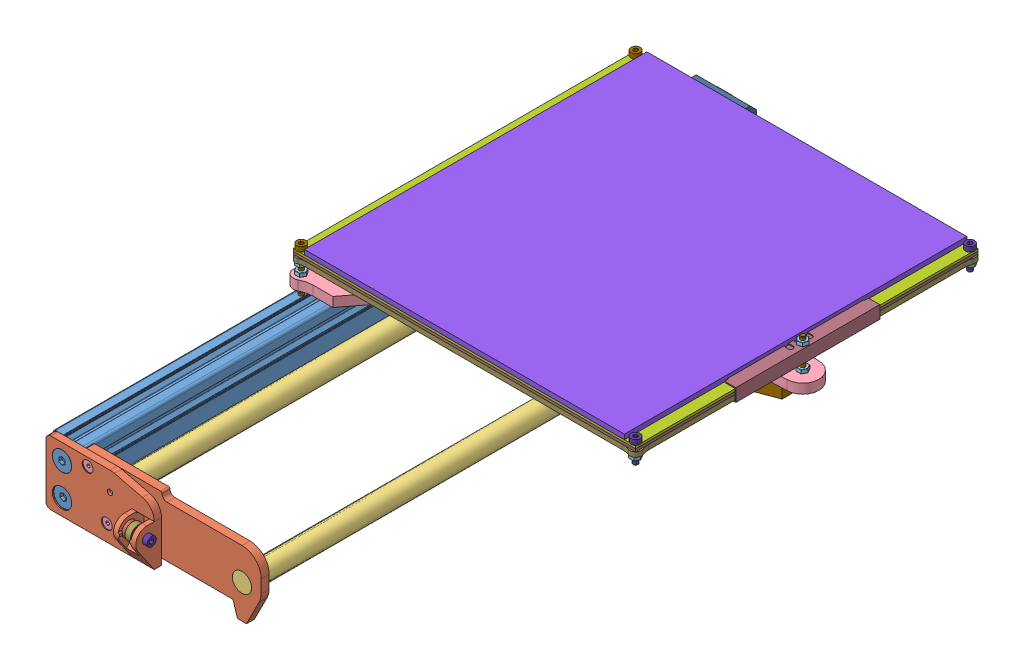
SolidWorks assembly 750Y, configuration Default. Lengths in mm.
Overall size (237.4 78 421.57).
82 component instances, 32 part files, 159 mates.
Components (placement in the parent):
- 458-1: 458 [Default] at origin size (20 40 350)
- 547-1: 547 [Default] at (0 10 350) size (67.7 40 32.1)
- 402-1: 402 [Default] at (30 18 0) x (0.324904 -0.945747 0) z (0 0 1) size (12 12 350)
- 681-1: 681 [Default] at (101.9 38 97.838) x (0 0 -1) z (0 1 0) size (219 224 6)
- 444-1: 444 [Default] at (30 18 36.838) x (0.795933 -0.605384 0) z (0 0 1) size (21 21 30)
- 444-2: 444 [Default] at (30 18 128.838) x (0.061759 0.998091 0) z (0 0 1) size (21 21 30)
- 549-4: 549 [Default] at (30 18 128.838) x (0 -1 0) z (0 0 1) size (36.4 41.5 26)
- 550-4: 550 [Default] at (30 18 66.838) x (0 1 0) z (0 0 -1) size (36.4 41.5 37)
- 529-1: 529 [Default] at (13.5 18 97.838) x (0 0 -1) z (1 0 0) size (172 46 6)
- 530-1: 530 [Default] at (30 18 94.838) size (183 47.02 6)
- 408-1: 408 [Default] at (-0.75 9 -25.7) x (0 0 1) z (1 0 0) size (50.7 42 57.75)
- 548-1: 548 [Default] at (0 10 0) x (1 0 0) z (0 0 -1) size (48 42 66.5)
- 279-1: 279 [Default] at (51.2 7.9393 358.0393) x (0 0.707107 0.707107) z (1 0 0) size (10 10 4)
- 1047-2: 1047 [Default] at (101.9 56.1 97.838) x (0 0 1) z (0 -1 0) size (214 214 1.6)
- 543-3: 543 [Default] at (41 5 58.838) x (0 -0.961946 -0.273238) z (1 0 0) size (5.7 5.7 33)
- 543-4: 543 [Default] at (41 5 136.838) x (0 -0.299784 -0.954007) z (1 0 0) size (5.7 5.7 33)
- 543-5: 543 [Default] at (41 31 58.838) x (0 0.49265 -0.870228) z (1 0 0) size (5.7 5.7 33)
- 429-1: 429 [Default] at (36.325 -6.5 -41.2) x (0 0 -1) z (1 0 0) size (6.75 6.75 8)
- 429-2: 429 [Default] at (36.325 24.5 -10.2) x (0 0 -1) z (1 0 0) size (6.75 6.75 8)
- 116-3: 116 [Default] at (14.95 0.1 11) x (0 0 -1) z (1 0 0) size (7.8 7.8 12)
- 116-4: 116 [Default] at (15 0 339) x (0 0 -1) z (1 0 0) size (7.8 7.8 12)
- 257-1: 257 [Default] at (57.7 9 359.1) x (0 0 -1) z (1 0 0) size (5.7 5.7 15)
- 543-6: 543 [Default] at (41 31 136.838) x (0 -0.999989 -0.004729) z (1 0 0) size (5.7 5.7 33)
- 212-1: 212 [Default] at (28 18 143.322) x (1 0 0) z (0 0 -1) size (7 7 0.5)
- 414-1: 414 [Default] at (0 20 351.5) size (12 12 16)
- 414-2: 414 [Default] at (0 0 350.7) size (12 12 16)
- 414-3: 414 [Default] at (0 20 -6.65) size (12 12 16)
- 414-4: 414 [Default] at (0 0 -6.65) size (12 12 16)
- 531-1: 531 [Default] at (30 18 0) size (115 45 5)
- 402-2: 402 [Default] at (108 6 0) x (-0.810971 0.585087 0) z (0 0 1) size (12 12 350)
- 531-2: 531 [Default] at (30 18 345) size (115 45 5)
- 444-3: 444 [Default] at (108 6 112.838) x (0.977925 0.208956 0) z (0 0 -1) size (21 21 30)
- 185-1: 185 [Default] at (38 14.1 -5.2) x (0 -1 0) z (1 0 0) size (20 11 6)
- 466-1: 466 [Default] at (16 25 -5.575) size (6.75 6.75 12)
- 466-2: 466 [Default] at (28 0 -5.575) size (6.75 6.75 12)
- 258-1: 258 [Default] at (16 25 342.6) size (6.35 5.5 2.4)
- 258-2: 258 [Default] at (28 0 345) x (-0.5 -0.866025 0) z (0 0 -1) size (6.35 5.5 2.4)
- 465-1: 465 [Default] at (-18 -6.5 -10.2) x (0 0.234808 0.972042) z (-1 0 0) size (5.7 5.7 53)
- 466-3: 466 [Default] at (28 0 352.275) size (6.75 6.75 12)
- 258-3: 258 [Default] at (28 0 5) size (6.35 5.5 2.4)
- 466-4: 466 [Default] at (16 25 352.275) size (6.75 6.75 12)
- 258-4: 258 [Default] at (16 25 5) x (-0.923728 -0.383049 0) z (0 0 -1) size (6.35 5.5 2.4)
- 498-1: 498 [Default] at (101.9 57.6 97.838) x (0 0 1) z (0 -1 0) size (214 214 1.5)
- 125-1: 125 [Default] at (101.9 57.6 97.838) x (0 0 1) z (0 1 0) size (214 200 3)
- 112-9: 112 [Default] at (-2.6 57.6 202.338) x (0.999023 0 -0.04419) z (0 1 0) size (5.7 5.7 28)
- 258-5: 258 [Default] at (-2.6 49.1 202.338) x (1 0 0) z (0 1 0) size (6.35 5.5 2.4)
- 112-10: 112 [Default] at (206.4 38 97.838) x (0.57539 0 0.817879) z (0 -1 0) size (5.7 5.7 28)
- 257-9: 257 [Default] at (206.4 57.6 -6.662) x (1 0 0) z (0 1 0) size (5.7 5.7 15)
- 112-11: 112 [Default] at (-2.6 57.6 -6.662) x (1 0 0) z (0 1 0) size (5.7 5.7 28)
- 257-10: 257 [Default] at (206.4 57.6 202.338) x (-0.938216 0 0.34605) z (0 1 0) size (5.7 5.7 15)
- 258-6: 258 [Default] at (206.4 49.1 -6.662) x (1 0 0) z (0 1 0) size (6.35 5.5 2.4)
- 258-7: 258 [Default] at (206.4 58.6967 97.838) x (0.969959 0 -0.24327) z (0 1 0) size (6.35 5.5 2.4)
- 258-8: 258 [Default] at (206.4 49.1 202.338) x (1 0 -0.000756) z (0 1 0) size (6.35 5.5 2.4)
- 258-9: 258 [Default] at (206.4 52.1 97.838) x (0.866025 0 0.5) z (0 1 0) size (6.35 5.5 2.4)
- 258-10: 258 [Default] at (-2.6 49.1 -6.662) x (1 0 0) z (0 1 0) size (6.35 5.5 2.4)
- 497-3: 497 [Default] at (4 0 342) x (0 -1 0) z (1 0 0) size (16 6 5.5)
- 258-13: 258 [Default] at (206.4 44 97.838) x (1 0 0) z (0 1 0) size (6.35 5.5 2.4)
- 258-14: 258 [Default] at (-2.6 44 202.338) x (1 0 0) z (0 1 0) size (6.35 5.5 2.4)
- 258-15: 258 [Default] at (-2.6 44 -6.662) x (1 0 0) z (0 1 0) size (6.35 5.5 2.4)
- 258-16: 258 [Default] at (47.5 30.1 97.838) x (0 0 -1) z (0 1 0) size (6.35 5.5 2.4)
- 212-2: 212 [Default] at (47.5 32.5 97.838) x (1 0 0) z (0 1 0) size (7 7 0.5)
- 544-5: 544 [Default] at (47.5 43.725 97.838) x (1 0 0) z (0 1 0) size (6.75 6.75 16)
- 544-7: 544 [Default] at (16.5 43.725 69.838) x (-0.20031 0 -0.979733) z (0 1 0) size (6.75 6.75 16)
- 544-8: 544 [Default] at (16.5 43.725 125.838) x (1 0 0) z (0 1 0) size (6.75 6.75 16)
- 258-17: 258 [Default] at (16.5 30.1 69.838) x (0.5 0 0.866025) z (0 1 0) size (6.35 5.5 2.4)
- 258-18: 258 [Default] at (16.5 30.1 125.838) x (0.5 0 0.866025) z (0 1 0) size (6.35 5.5 2.4)
- 212-3: 212 [Default] at (16.5 32.5 125.838) x (0.9987 0 -0.050978) z (0 1 0) size (7 7 0.5)
- 212-4: 212 [Default] at (16.5 32.5 69.838) x (0.896423 0 -0.443199) z (0 1 0) size (7 7 0.5)
- 497-4: 497 [Default] at (4 0.1 14) x (0 -1 0) z (1 0 0) size (16 6 5.5)
- 258-19: 258 [Default] at (11.1 5 136.838) x (0 -0.988673 0.150084) z (1 0 0) size (6.35 5.5 2.4)
- 258-21: 258 [Default] at (11.1 31 58.838) x (0 -0.988673 0.150084) z (1 0 0) size (6.35 5.5 2.4)
- 258-22: 258 [Default] at (11.1 5 58.838) x (0 -0.988673 0.150084) z (1 0 0) size (6.35 5.5 2.4)
- 258-23: 258 [Default] at (11.1 31 136.838) x (0 -0.988673 0.150084) z (1 0 0) size (6.35 5.5 2.4)
- 544-9: 544 [Default] at (147.5 43.725 97.838) x (1 0 0) z (0 1 0) size (6.75 6.75 16)
- 258-24: 258 [Default] at (147.5 30.1 97.838) x (0 0 -1) z (0 1 0) size (6.35 5.5 2.4)
- 212-5: 212 [Default] at (147.5 32.5 97.838) x (1 0 0) z (0 1 0) size (7 7 0.5)
- 258-25: 258 [Default] at (-2.6 35.6 202.338) x (1 0 0) z (0 1 0) size (6.35 5.5 2.4)
- 258-26: 258 [Default] at (-2.6 35.6 -6.662) x (1 0 0) z (0 1 0) size (6.35 5.5 2.4)
- 1044-1: 1044 [Default] at (101.9 51.5 97.838) x (0 0 -1) z (0 1 0) size (216.07 216.07 3)
- 575-1: 575 [Default] at (209.5 54.5281 97.838) x (0 0 1) z (-1 0 0) size (90 8 28.3)
- 461-1: 461 [Default] at (-8.542 38.3733 30.9668) size (4.5 4.5 12.5)
- 461-2: 461 [Default] at (-8.5585 42.2431 13.8478) size (4.5 4.5 12.5)
Mates (geometry in assembly coordinates):
- Coincident60: coincident anti-aligned: plane of 547-1 through (-7 -7 350) normal (0 0 -1); plane of 458-1 through (9.8 -3.75 350) normal (0 0 1)
- Coincident121: coincident anti-aligned: plane of 458-1 through (9.8 -3.75 0) normal (0 0 -1); plane of 548-1 through (0 10 0) normal (0 0 1)
- Parallel12: parallel aligned: plane of 458-1 through (10 16.3 350) normal (1 0 0); plane of 548-1 through (38 -12 -4.5) normal (1 0 0)
- Concentric67: concentric aligned: cylinder of 458-1 through (0 20 350) axis (0 0 -1) radius 2.75; cylinder of 547-1 through (0 20 354.5) axis (0 0 -1) radius 3.1
- Concentric235: concentric aligned: cylinder of 458-1 through (0 0 350) axis (0 0 -1) radius 2.75; cylinder of 547-1 through (0 0 354.5) axis (0 0 -1) radius 3.1
- Concentric243: concentric anti-aligned: cylinder of 458-1 through (0 20 350) axis (0 0 -1) radius 2.75; cylinder of 548-1 through (0 20 -4.5) axis (0 0 1) radius 3.15
- Concentric68: concentric anti-aligned: cylinder of 547-1 through (-10 9 359.1) axis (1 0 0) radius 1.65; cylinder of 279-1 through (53.7 9 359.1) axis (-1 0 0) radius 1.5
- Coincident127: coincident anti-aligned: plane of 547-1 through (48.7 9 359.1) normal (1 0 0); plane of 279-1 through (48.7 10.0607 360.1607) normal (-1 0 0)
- Concentric164: concentric aligned: cylinder of 116-4 through (5.3 0 339) axis (1 0 0) radius 2; cylinder of 547-1 through (-10 0 339) axis (1 0 0) radius 2.1
- Coincident217: coincident: cone of 547-1 through (15.5 0 339) axis (-1 0 0); circle of 116-4
- Concentric165: concentric aligned: cylinder of 547-1 through (-10 9 359.1) axis (1 0 0) radius 1.65; cylinder of 257-1 through (45.7 9 359.1) axis (1 0 0) radius 1.5
- Coincident218: coincident anti-aligned: plane of 547-1 through (57.7 30 354.5) normal (1 0 0); plane of 257-1 through (57.7 9 359.1) normal (-1 0 0)
- Coincident277: coincident: cone of 547-1 through (0 0 353.8) axis (0 0 -1); circle of 414-2
- Coincident278: coincident aligned: plane of 547-1 through (-7 -7 354.5) normal (0 0 1); circle of 414-1
- Concentric234: concentric anti-aligned: cylinder of 547-1 through (0 0 354.5) axis (0 0 -1) radius 3.1; cylinder of 414-2 through (0 0 337.7) axis (0 0 1) radius 3
- Concentric240: concentric anti-aligned: cylinder of 547-1 through (0 20 354.5) axis (0 0 -1) radius 3.1; cylinder of 414-1 through (0 20 338.5) axis (0 0 1) radius 3
- Concentric251: concentric anti-aligned: cylinder of 547-1 through (16 25 366.1) axis (0 0 -1) radius 1.65; cylinder of 466-4 through (16 25 341.925) axis (0 0 1) radius 1.5
- Coincident302: coincident: cone of 547-1 through (16 25 352.2) axis (0 0 -1); circle of 466-4
- Concentric252: concentric anti-aligned: cylinder of 547-1 through (28 0 366.1) axis (0 0 -1) radius 1.65; cylinder of 466-3 through (28 0 341.925) axis (0 0 1) radius 1.5
- Coincident303: coincident: cone of 547-1 through (28 0 352.2) axis (0 0 -1); circle of 466-3
- Concentric56: concentric anti-aligned: cylinder of 402-1 through (30 18 350) axis (0 0 -1) radius 6; cylinder of 444-1 through (30 18 36.838) axis (0 0 1) radius 6
- Concentric95: concentric anti-aligned: cylinder of 402-1 through (30 18 350) axis (0 0 -1) radius 6; cylinder of 444-2 through (30 18 128.838) axis (0 0 1) radius 6
- Concentric231: concentric aligned: cylinder of 402-1 through (30 18 350) axis (0 0 -1) radius 6; cylinder of 531-2 through (30 18 350) axis (0 0 -1) radius 5.98
- Concentric85: concentric anti-aligned: cylinder of 1047-2 through (-2.6 54.5 -6.662) axis (0 1 0) radius 1.5; cylinder of 681-1 through (-2.6 44 -6.662) axis (0 -1 0) radius 1.5
- Coincident300: coincident anti-aligned: plane of 681-1 through (-20.1 38 3.0204) normal (0 -1 0); plane of 529-1 through (19.5 38 105.338) normal (0 1 0)
- Width10: width anti-aligned: plane of 681-1 through (194.5 44 100.888) normal (-1 0 0); plane of 681-1 through (178.5 44 100.888) normal (1 0 0); plane of 530-1 through (194.5 44 100.838) normal (1 0 0); plane of 530-1 through (178.5 38 100.838) normal (-1 0 0)
- Width11: width anti-aligned: plane of 681-1 through (19.6 44 90.338) normal (0 0 1); plane of 681-1 through (19.6 44 105.338) normal (0 0 -1); plane of 529-1 through (19.5 38 90.338) normal (0 0 -1); plane of 529-1 through (19.5 38 105.338) normal (0 0 1)
- Concentric148: concentric aligned: cylinder of 444-1 through (30 18 36.838) axis (0 0 1) radius 10.5; cylinder of 550-4 through (30 18 40.838) axis (0 0 1) radius 10.5
- Coincident299: coincident aligned: plane of 550-4 through (30 18 66.838) normal (0 0 1); plane of 444-1 through (34.7756 14.3677 66.838) normal (0 0 1)
- Concentric97: concentric anti-aligned: cylinder of 444-2 through (30 18 128.838) axis (0 0 1) radius 10.5; cylinder of 549-4 through (30 18 154.838) axis (0 0 -1) radius 10.5
- Coincident298: coincident aligned: plane of 549-4 through (30 18 128.838) normal (0 0 -1); plane of 444-2 through (30.6485 28.48 128.838) normal (0 0 -1)
- Width13: width anti-aligned: plane of 529-1 through (19.5 44 100.838) normal (0 0 -1); plane of 529-1 through (19.5 44 94.838) normal (0 0 1); plane of 530-1 through (30 18 100.838) normal (0 0 1); plane of 530-1 through (30 18 94.838) normal (0 0 -1)
- Concentric106: concentric aligned: cylinder of 529-1 through (13.5 5 58.838) axis (1 0 0) radius 2; cylinder of 543-3 through (11 5 58.838) axis (1 0 0) radius 1.5
- Concentric107: concentric aligned: cylinder of 529-1 through (13.5 5 136.838) axis (1 0 0) radius 2; cylinder of 543-4 through (11 5 136.838) axis (1 0 0) radius 1.5
- Concentric147: concentric aligned: cylinder of 529-1 through (13.5 31 58.838) axis (1 0 0) radius 2; cylinder of 543-5 through (11 31 58.838) axis (1 0 0) radius 1.5
- Concentric166: concentric aligned: cylinder of 529-1 through (13.5 31 136.838) axis (1 0 0) radius 2; cylinder of 543-6 through (11 31 136.838) axis (1 0 0) radius 1.5
- Width9: width aligned: plane of 444-3 through (118.2682 8.194 112.838) normal (0 0 1); plane of 444-3 through (113.8676 7.2537 82.838) normal (0 0 -1); plane of 530-1 through (30 18 100.838) normal (0 0 1); plane of 530-1 through (30 18 94.838) normal (0 0 -1)
- Concentric250: concentric aligned: cylinder of 530-1 through (108 6 100.838) axis (0 0 -1) radius 10.45; cylinder of 444-3 through (108 6 112.838) axis (0 0 -1) radius 10.5
- Coincident123: coincident anti-aligned: plane of 408-1 through (33 9 -25.7) normal (1 0 0); plane of 548-1 through (33 30 -50.5) normal (-1 0 0)
- Parallel26: parallel aligned: plane of 408-1 through (33 -8.007 -4.7) normal (0 0 1); plane of 548-1 through (0 10 0) normal (0 0 1)
- Concentric143: concentric aligned: cylinder of 408-1 through (35 9 -25.7) axis (-1 0 0) radius 11; cylinder of 548-1 through (38.0001 9 -25.7) axis (-1 0 0) radius 11.1
- Concentric163: concentric anti-aligned: cone of 548-1 through (17.5 0.1 11) axis (-1 0 0); cylinder of 116-3 through (5.25 0.1 11) axis (1 0 0) radius 2
- Coincident216: coincident: cone of 548-1 through (17.5 0.1 11) axis (-1 0 0); circle of 116-3
- Concentric209: concentric aligned: cylinder of 548-1 through (0 0 -4.5) axis (0 0 1) radius 3.15; cylinder of 414-4 through (0 0 -19.65) axis (0 0 1) radius 3
- Coincident273: coincident: cone of 548-1 through (0 0 -3.8) axis (0 0 1); circle of 414-4
- Concentric210: concentric aligned: cylinder of 548-1 through (0 20 -4.5) axis (0 0 1) radius 3.15; cylinder of 414-3 through (0 20 -19.65) axis (0 0 1) radius 3
- Coincident274: coincident: cone of 548-1 through (0 20 -3.8) axis (0 0 1); circle of 414-3
- Coincident291: coincident anti-aligned: plane of 548-1 through (0 10 0) normal (0 0 1); plane of 531-1 through (10 23.8 0) normal (0 0 -1)
- Parallel36: parallel anti-aligned: plane of 548-1 through (10 -6 16) normal (0 1 0); plane of 531-1 through (10.8 -6 5) normal (0 -1 0)
- Concentric244: concentric aligned: cylinder of 548-1 through (16 25 -50.501) axis (0 0 1) radius 1.65; cylinder of 466-1 through (16 25 -15.925) axis (0 0 1) radius 1.5
- Coincident293: coincident: cone of 548-1 through (16 25 -2.2) axis (0 0 1); circle of 466-1
- Concentric245: concentric aligned: cylinder of 548-1 through (28 0 -50.501) axis (0 0 1) radius 1.65; cylinder of 466-2 through (28 0 -15.925) axis (0 0 1) radius 1.5
- Coincident294: coincident: cone of 548-1 through (28 0 -2.2) axis (0 0 1); circle of 466-2
- Coincident304: coincident aligned: plane of 531-1 through (10 23.8 5) normal (0 0 1); plane of 258-4 through (16 25 5) normal (0 0 1)
- Coincident305: coincident anti-aligned: plane of 531-1 through (10 23.8 5) normal (0 0 1); plane of 258-3 through (28 0 5) normal (0 0 -1)
- Concentric232: concentric aligned: cylinder of 402-2 through (108 6 350) axis (0 0 -1) radius 6; cylinder of 531-2 through (108 6 350) axis (0 0 -1) radius 5.98
- Concentric233: concentric aligned: cylinder of 402-2 through (108 6 350) axis (0 0 -1) radius 6; cylinder of 444-3 through (108 6 112.838) axis (0 0 -1) radius 6
- Coincident295: coincident anti-aligned: plane of 531-2 through (10 23.8 345) normal (0 0 -1); plane of 258-1 through (16 25 345) normal (0 0 1)
- Coincident297: coincident anti-aligned: plane of 531-2 through (10 23.8 345) normal (0 0 -1); plane of 258-2 through (28 0 345) normal (0 0 1)
- Concentric246: concentric anti-aligned: cylinder of 466-1 through (16 25 -15.925) axis (0 0 1) radius 1.5; cylinder of 258-1 through (16 25 345) axis (0 0 -1) radius 1.25
- Concentric247: concentric aligned: cylinder of 466-2 through (28 0 -15.925) axis (0 0 1) radius 1.5; cylinder of 258-2 through (28 0 342.6) axis (0 0 1) radius 1.25
- Concentric254: concentric anti-aligned: cylinder of 466-3 through (28 0 341.925) axis (0 0 1) radius 1.5; cylinder of 258-3 through (28 0 7.4) axis (0 0 -1) radius 1.25
- Concentric253: concentric aligned: cylinder of 466-4 through (16 25 341.925) axis (0 0 1) radius 1.5; cylinder of 258-4 through (16 25 2.6) axis (0 0 1) radius 1.25
- Concentric255: concentric anti-aligned: cylinder of 681-1 through (206.4 44 97.838) axis (0 -1 0) radius 1.5; cylinder of 1047-2 through (206.4 54.5 97.838) axis (0 1 0) radius 1.5
- Coincident306: coincident anti-aligned: plane of 1047-2 through (101.9 56.1 97.838) normal (0 1 0); plane of 498-1 through (101.9 56.1 97.838) normal (0 -1 0)
- Coincident307: coincident aligned: plane of 1047-2 through (208.9 54.5 -9.162) normal (1 0 0); plane of 498-1 through (208.9 56.1 -9.162) normal (1 0 0)
- Coincident308: coincident aligned: plane of 1047-2 through (208.9 54.5 -9.162) normal (0 0 -1); plane of 498-1 through (208.9 56.1 -9.162) normal (0 0 -1)
- Coincident346: coincident anti-aligned: plane of 498-1 through (101.9 57.6 97.838) normal (0 1 0); plane of 125-1 through (101.9 57.6 97.838) normal (0 -1 0)
- Coincident348: coincident aligned: plane of 498-1 through (208.9 56.1 -9.162) normal (0 0 -1); plane of 125-1 through (201.9 60.6 -9.162) normal (0 0 -1)
- Width12: width aligned: plane of 498-1 through (-5.1 56.1 -9.162) normal (-1 0 0); plane of 498-1 through (208.9 56.1 -9.162) normal (1 0 0); plane of 125-1 through (1.9 60.6 -9.162) normal (-1 0 0); plane of 125-1 through (201.9 60.6 -9.162) normal (1 0 0)
- Concentric256: concentric anti-aligned: cylinder of 257-10 through (206.4 45.6 202.338) axis (0 1 0) radius 1.5; cylinder of 258-8 through (206.4 51.5 202.338) axis (0 -1 0) radius 1.25
- Concentric257: concentric anti-aligned: cylinder of 112-9 through (-2.6 32.6 202.338) axis (0 1 0) radius 1.5; cylinder of 258-5 through (-2.6 51.5 202.338) axis (0 -1 0) radius 1.25
- Concentric258: concentric anti-aligned: cylinder of 112-11 through (-2.6 32.6 -6.662) axis (0 1 0) radius 1.5; cylinder of 258-10 through (-2.6 51.5 -6.662) axis (0 -1 0) radius 1.25
- Concentric259: concentric aligned: cylinder of 498-1 through (206.4 56.1 202.338) axis (0 1 0) radius 1.6; cylinder of 257-10 through (206.4 45.6 202.338) axis (0 1 0) radius 1.5
- Coincident350: coincident anti-aligned: plane of 498-1 through (101.9 57.6 97.838) normal (0 1 0); plane of 257-10 through (206.4 57.6 202.338) normal (0 -1 0)
- Coincident352: coincident anti-aligned: plane of 498-1 through (101.9 57.6 97.838) normal (0 1 0); plane of 112-9 through (-2.6 57.6 202.338) normal (0 -1 0)
- Concentric260: concentric aligned: cylinder of 498-1 through (-2.6 56.1 202.338) axis (0 1 0) radius 1.6; cylinder of 112-9 through (-2.6 32.6 202.338) axis (0 1 0) radius 1.5
- Coincident354: coincident anti-aligned: plane of 498-1 through (101.9 57.6 97.838) normal (0 1 0); plane of 112-11 through (-2.6 57.6 -6.662) normal (0 -1 0)
- Concentric261: concentric aligned: cylinder of 498-1 through (-2.6 56.1 -6.662) axis (0 1 0) radius 1.6; cylinder of 112-11 through (-2.6 32.6 -6.662) axis (0 1 0) radius 1.5
- Concentric262: concentric anti-aligned: cylinder of 1047-2 through (206.4 54.5 97.838) axis (0 1 0) radius 1.5; cylinder of 112-10 through (206.4 63 97.838) axis (0 -1 0) radius 1.5
- Concentric263: concentric aligned: cylinder of 498-1 through (206.4 56.1 -6.662) axis (0 1 0) radius 1.6; cylinder of 257-9 through (206.4 45.6 -6.662) axis (0 1 0) radius 1.5
- Coincident356: coincident anti-aligned: plane of 1047-2 through (101.9 54.5 97.838) normal (0 -1 0); plane of 258-9 through (206.4 54.5 97.838) normal (0 1 0)
- Concentric264: concentric aligned: cylinder of 112-10 through (206.4 63 97.838) axis (0 -1 0) radius 1.5; cylinder of 258-9 through (206.4 54.5 97.838) axis (0 -1 0) radius 1.25
- Concentric265: concentric anti-aligned: cylinder of 257-9 through (206.4 45.6 -6.662) axis (0 1 0) radius 1.5; cylinder of 258-6 through (206.4 51.5 -6.662) axis (0 -1 0) radius 1.25
- Coincident358: coincident anti-aligned: plane of 498-1 through (101.9 57.6 97.838) normal (0 1 0); plane of 257-9 through (206.4 57.6 -6.662) normal (0 -1 0)
- Concentric266: concentric aligned: cylinder of 112-10 through (206.4 63 97.838) axis (0 -1 0) radius 1.5; cylinder of 258-7 through (206.4 61.0967 97.838) axis (0 -1 0) radius 1.25
- Concentric267: concentric aligned: cylinder of 116-4 through (5.3 0 339) axis (1 0 0) radius 2; cylinder of 497-3 through (4 0 339) axis (1 0 0) radius 1.65
- Parallel37: parallel aligned: plane of 547-1 through (-7 -7 354.5) normal (0 0 1); plane of 497-3 through (4 0 342) normal (0 0 1)
- Coincident361: coincident anti-aligned: plane of 458-1 through (8.5 3.45 350) normal (-1 0 0); plane of 497-3 through (8.5 8 336) normal (1 0 0)
- Concentric270: concentric anti-aligned: cylinder of 112-11 through (-2.6 32.6 -6.662) axis (0 1 0) radius 1.5; cylinder of 258-15 through (-2.6 46.4 -6.662) axis (0 -1 0) radius 1.25
- Concentric271: concentric anti-aligned: cylinder of 112-9 through (-2.6 32.6 202.338) axis (0 1 0) radius 1.5; cylinder of 258-14 through (-2.6 46.4 202.338) axis (0 -1 0) radius 1.25
- Concentric272: concentric aligned: cylinder of 112-10 through (206.4 63 97.838) axis (0 -1 0) radius 1.5; cylinder of 258-13 through (206.4 46.4 97.838) axis (0 -1 0) radius 1.25
- Coincident368: coincident anti-aligned: plane of 681-1 through (-20.1 44 3.0204) normal (0 1 0); plane of 258-13 through (206.4 44 97.838) normal (0 -1 0)
- Concentric273: concentric anti-aligned: cylinder of 681-1 through (47.5 44 97.838) axis (0 -1 0) radius 2; cylinder of 544-5 through (47.5 29.375 97.838) axis (0 1 0) radius 1.5
- Concentric274: concentric anti-aligned: cylinder of 258-16 through (47.5 32.5 97.838) axis (0 -1 0) radius 1.25; cylinder of 544-5 through (47.5 29.375 97.838) axis (0 1 0) radius 1.5
- Concentric275: concentric anti-aligned: cylinder of 212-2 through (47.5 33 97.838) axis (0 -1 0) radius 1.6; cylinder of 544-5 through (47.5 29.375 97.838) axis (0 1 0) radius 1.5
- Concentric276: concentric anti-aligned: cylinder of 681-1 through (16.5 44 125.838) axis (0 -1 0) radius 2; cylinder of 544-8 through (16.5 29.375 125.838) axis (0 1 0) radius 1.5
- Concentric277: concentric anti-aligned: cylinder of 544-8 through (16.5 29.375 125.838) axis (0 1 0) radius 1.5; cylinder of 258-18 through (16.5 32.5 125.838) axis (0 -1 0) radius 1.25
- Concentric278: concentric anti-aligned: cylinder of 544-8 through (16.5 29.375 125.838) axis (0 1 0) radius 1.5; cylinder of 212-3 through (16.5 33 125.838) axis (0 -1 0) radius 1.6
- Concentric279: concentric anti-aligned: cylinder of 681-1 through (16.5 44 69.838) axis (0 -1 0) radius 2; cylinder of 544-7 through (16.5 29.375 69.838) axis (0 1 0) radius 1.5
- Concentric280: concentric anti-aligned: cylinder of 544-7 through (16.5 29.375 69.838) axis (0 1 0) radius 1.5; cylinder of 258-17 through (16.5 32.5 69.838) axis (0 -1 0) radius 1.25
- Concentric281: concentric anti-aligned: cylinder of 544-7 through (16.5 29.375 69.838) axis (0 1 0) radius 1.5; cylinder of 212-4 through (16.5 33 69.838) axis (0 -1 0) radius 1.6
- Coincident371: coincident anti-aligned: plane of 530-1 through (46.02 33 100.838) normal (0 -1 0); plane of 212-2 through (47.5 33 97.838) normal (0 1 0)
- Coincident372: coincident anti-aligned: plane of 258-16 through (47.5 32.5 97.838) normal (0 1 0); plane of 212-2 through (47.5 32.5 97.838) normal (0 -1 0)
- Parallel38: parallel anti-aligned: plane of 530-1 through (44.8 32.5 100.838) normal (1 0 0); plane of 258-16 through (44.75 32.5 96.2502) normal (-1 0 0)
- Coincident373: coincident: circle of 681-1; cone of 544-5 through (47.5 45.375 97.838) axis (0 -1 0)
- Coincident374: coincident anti-aligned: plane of 258-17 through (16.5 32.5 69.838) normal (0 1 0); plane of 212-4 through (16.5 32.5 69.838) normal (0 -1 0)
- Coincident375: coincident anti-aligned: plane of 529-1 through (13.5 33 71.318) normal (0 -1 0); plane of 212-4 through (16.5 33 69.838) normal (0 1 0)
- Parallel39: parallel anti-aligned: plane of 529-1 through (13.5 32.5 72.538) normal (0 0 -1); plane of 258-17 through (14.9123 32.5 72.588) normal (0 0 1)
- Coincident376: coincident: circle of 681-1; cone of 544-7 through (16.5 45.375 69.838) axis (0 -1 0)
- Coincident377: coincident anti-aligned: plane of 258-18 through (16.5 32.5 125.838) normal (0 1 0); plane of 212-3 through (16.5 32.5 125.838) normal (0 -1 0)
- Coincident378: coincident anti-aligned: plane of 529-1 through (13.5 33 127.318) normal (0 -1 0); plane of 212-3 through (16.5 33 125.838) normal (0 1 0)
- Parallel40: parallel anti-aligned: plane of 529-1 through (13.5 32.5 128.538) normal (0 0 -1); plane of 258-18 through (14.9123 32.5 128.588) normal (0 0 1)
- Coincident379: coincident: circle of 681-1; cone of 544-8 through (16.5 45.375 125.838) axis (0 -1 0)
- Concentric282: concentric aligned: cylinder of 116-3 through (5.25 0.1 11) axis (1 0 0) radius 2; cylinder of 497-4 through (4 0.1 11) axis (1 0 0) radius 1.65
- Coincident380: coincident anti-aligned: plane of 458-1 through (8.5 -3.55 350) normal (-1 0 0); plane of 497-4 through (8.5 -7.9 8) normal (1 0 0)
- Coincident385: coincident aligned: plane of 529-1 through (19.5 25 33.838) normal (1 0 0); plane of 530-1 through (19.5 44 100.838) normal (1 0 0)
- Coincident388: coincident anti-aligned: plane of 549-4 through (19.5 33 154.838) normal (-1 0 0); plane of 529-1 through (19.5 25 33.838) normal (1 0 0)
- Concentric285: concentric anti-aligned: cylinder of 549-4 through (55 31 136.838) axis (-1 0 0) radius 1.65; cylinder of 529-1 through (13.5 31 136.838) axis (1 0 0) radius 2
- Coincident389: coincident anti-aligned: plane of 550-4 through (19.5 26 40.838) normal (-1 0 0); plane of 529-1 through (19.5 25 33.838) normal (1 0 0)
- Concentric286: concentric anti-aligned: cylinder of 550-4 through (45 5 58.838) axis (-1 0 0) radius 1.65; cylinder of 529-1 through (13.5 5 58.838) axis (1 0 0) radius 2
- Coincident390: coincident anti-aligned: plane of 547-1 through (-7 -7 350) normal (0 0 -1); plane of 531-2 through (10 23.8 350) normal (0 0 1)
- Coincident392: coincident aligned: plane of 402-1 through (30 18 350) normal (0 0 1); plane of 531-2 through (10 23.8 350) normal (0 0 1)
- Concentric288: concentric aligned: cylinder of 547-1 through (16 25 366.1) axis (0 0 -1) radius 1.65; cylinder of 531-2 through (16 25 350) axis (0 0 -1) radius 1.65
- Coincident393: coincident anti-aligned: plane of 547-1 through (57.7 -6 354.5) normal (0 1 0); plane of 531-2 through (10.8 -6 350) normal (0 -1 0)
- Coincident394: coincident aligned: plane of 402-2 through (108 6 350) normal (0 0 1); plane of 531-2 through (10 23.8 350) normal (0 0 1)
- Coincident395: coincident anti-aligned: plane of 549-4 through (41 5 136.838) normal (1 0 0); plane of 543-4 through (41 5 136.838) normal (-1 0 0)
- Concentric289: concentric anti-aligned: cylinder of 543-4 through (11 5 136.838) axis (1 0 0) radius 1.5; cylinder of 258-19 through (13.5 5 136.838) axis (-1 0 0) radius 1.25
- Concentric290: concentric aligned: cylinder of 402-1 through (30 18 350) axis (0 0 -1) radius 6; cylinder of 531-1 through (30 18 5) axis (0 0 -1) radius 5.98
- Concentric291: concentric aligned: cylinder of 408-1 through (28 24.5 -10.2) axis (1 0 0) radius 1.5; cylinder of 429-2 through (29.975 24.5 -10.2) axis (1 0 0) radius 1.5
- Concentric292: concentric aligned: cylinder of 408-1 through (28 -6.5 -41.2) axis (1 0 0) radius 1.5; cylinder of 429-1 through (29.975 -6.5 -41.2) axis (1 0 0) radius 1.5
- Concentric293: concentric aligned: cylinder of 408-1 through (4.25 -6.5 -10.2) axis (-1 0 0) radius 1.5; cylinder of 465-1 through (32 -6.5 -10.2) axis (-1 0 0) radius 1.5
- Coincident396: coincident anti-aligned: plane of 529-1 through (13.5 25 33.838) normal (-1 0 0); plane of 258-19 through (13.5 5 136.838) normal (1 0 0)
- Coincident397: coincident anti-aligned: plane of 550-4 through (41 5 58.838) normal (1 0 0); plane of 543-3 through (41 5 58.838) normal (-1 0 0)
- Coincident399: coincident anti-aligned: plane of 550-4 through (41 31 58.838) normal (1 0 0); plane of 543-5 through (41 31 58.838) normal (-1 0 0)
- Coincident400: coincident anti-aligned: plane of 549-4 through (41 31 136.838) normal (1 0 0); plane of 543-6 through (41 31 136.838) normal (-1 0 0)
- Concentric294: concentric aligned: cylinder of 543-5 through (44 31 58.838) axis (-1 0 0) radius 2.85; cylinder of 258-21 through (13.5 31 58.838) axis (-1 0 0) radius 1.25
- Concentric295: concentric aligned: cylinder of 543-3 through (44 5 58.838) axis (-1 0 0) radius 2.85; cylinder of 258-22 through (13.5 5 58.838) axis (-1 0 0) radius 1.25
- Concentric296: concentric aligned: cylinder of 543-6 through (44 31 136.838) axis (-1 0 0) radius 2.85; cylinder of 258-23 through (13.5 31 136.838) axis (-1 0 0) radius 1.25
- Coincident401: coincident anti-aligned: plane of 529-1 through (13.5 25 33.838) normal (-1 0 0); plane of 258-23 through (13.5 31 136.838) normal (1 0 0)
- Coincident403: coincident anti-aligned: plane of 529-1 through (13.5 25 33.838) normal (-1 0 0); plane of 258-21 through (13.5 31 58.838) normal (1 0 0)
- Coincident404: coincident anti-aligned: plane of 529-1 through (13.5 25 33.838) normal (-1 0 0); plane of 258-22 through (13.5 5 58.838) normal (1 0 0)
- Concentric297: concentric anti-aligned: cylinder of 544-9 through (147.5 29.375 97.838) axis (0 1 0) radius 1.5; cylinder of 212-5 through (147.5 33 97.838) axis (0 -1 0) radius 1.6
- Concentric298: concentric anti-aligned: cylinder of 544-9 through (147.5 29.375 97.838) axis (0 1 0) radius 1.5; cylinder of 258-24 through (147.5 32.5 97.838) axis (0 -1 0) radius 1.25
- Coincident405: coincident anti-aligned: plane of 258-24 through (147.5 32.5 97.838) normal (0 1 0); plane of 212-5 through (147.5 32.5 97.838) normal (0 -1 0)
- Coincident406: coincident anti-aligned: plane of 530-1 through (146.02 33 100.838) normal (0 -1 0); plane of 212-5 through (147.5 33 97.838) normal (0 1 0)
- Coincident407: coincident: circle of 681-1; cone of 544-9 through (147.5 45.375 97.838) axis (0 -1 0)
- Coincident408: coincident anti-aligned: plane of 681-1 through (-20.1 38 3.0204) normal (0 -1 0); plane of 258-25 through (-2.6 38 202.338) normal (0 1 0)
- Concentric299: concentric anti-aligned: cylinder of 112-9 through (-2.6 32.6 202.338) axis (0 1 0) radius 1.5; cylinder of 258-25 through (-2.6 38 202.338) axis (0 -1 0) radius 1.25
- Coincident409: coincident anti-aligned: plane of 681-1 through (-20.1 38 3.0204) normal (0 -1 0); plane of 258-26 through (-2.6 38 -6.662) normal (0 1 0)
- Concentric300: concentric anti-aligned: cylinder of 112-11 through (-2.6 32.6 -6.662) axis (0 1 0) radius 1.5; cylinder of 258-26 through (-2.6 38 -6.662) axis (0 -1 0) radius 1.25
- Distance1: distance = 3 mm aligned: plane of 112-9 through (-2.6 32.6 202.338) normal (0 -1 0); plane of 258-25 through (-2.6 35.6 202.338) normal (0 -1 0)
- Coincident417: coincident anti-aligned: plane of 681-1 through (-20.1 44 3.0204) normal (0 1 0); plane of 258-14 through (-2.6 44 202.338) normal (0 -1 0)
- Coincident418: coincident anti-aligned: plane of 681-1 through (-20.1 44 3.0204) normal (0 1 0); plane of 258-15 through (-2.6 44 -6.662) normal (0 -1 0)
- Coincident419: coincident anti-aligned: plane of 681-1 through (-20.1 38 3.0204) normal (0 -1 0); plane of 112-10 through (206.4 38 97.838) normal (0 1 0)
- Concentric303: concentric anti-aligned: cylinder of 112-10 through (206.4 63 97.838) axis (0 -1 0) radius 1.5; cylinder of 575-1 through (206.4 50.5281 97.838) axis (0 1 0) radius 1.5
- Parallel41: parallel aligned: plane of 1047-2 through (208.9 54.5 -9.162) normal (1 0 0); plane of 575-1 through (209.5 54.5281 97.838) normal (1 0 0)
- Parallel42: parallel aligned: plane of 1047-2 through (208.9 54.5 -9.162) normal (1 0 0); plane of 258-9 through (209.15 54.5 99.4257) normal (1 0 0)
- Distance2: distance = 8 mm anti-aligned: plane of 465-1 through (-18 -6.5 -10.2) normal (1 0 0); plane of 548-1 through (-10 -12 -4.5) normal (-1 0 0)
